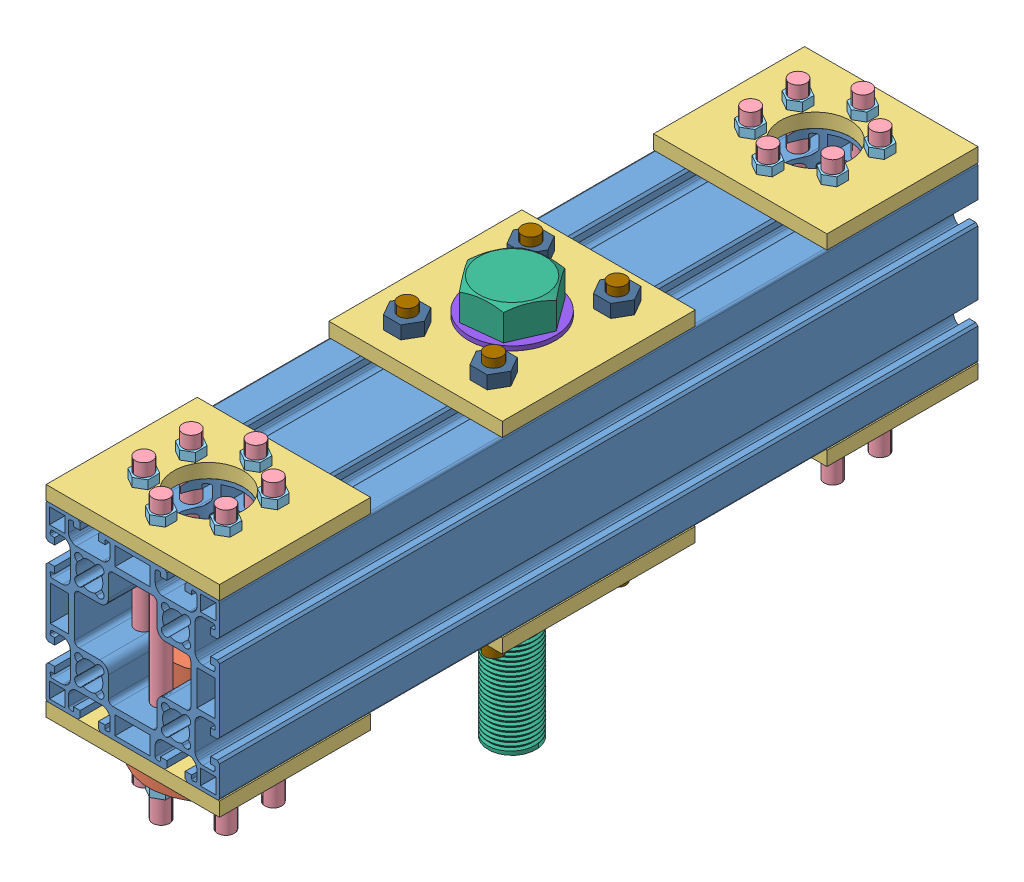
SolidWorks assembly loading_beaM_assembly, configuration Default. Lengths in mm.
Overall size (80.06 184 350).
17 component instances, 10 part files, 45 mates.
Components (placement in the parent):
- AL_profile350-1: AL_profile350 [Default] at (-39.8812 -129.6235 350) x (1 0 0) z (0 1 0) size (80 350 80)
- bearing for thread-1: bearing for thread [Default] at (-39.9881 -184.4189 315) size (55 44.2 55)
- metal piece-1: metal piece [Default] at (-39.9406 -79.4189 175) x (1 0 0) z (0 -1 0) size (80 350 6.5)
- side_threa_rods-1: side_threa_rods [Default] at (-39.9881 -199.4938 315) size (45.68 130 51.54)
- side_threa_rods-2: side_threa_rods [Default] at (-39.9881 -199.4938 35) x (0.5 0 -0.866025) z (0.866025 0 0.5) size (45.68 130 51.54)
- metal piece-3: metal piece [Default] at (-39.9406 -165.9189 175) x (1 0 0) z (0 -1 0) size (80 350 6.5)
- bearing for thread-2: bearing for thread [Default] at (-39.9881 -184.4189 35) size (55 44.2 55)
- nuts_7.8-1: nuts_7.8 [Default] at (-39.9881 -188.4189 315) size (47.17 4 54.47)
- nuts_7.8-2: nuts_7.8 [Default] at (-39.9881 -188.4189 35) size (47.17 4 54.47)
- nuts_7.8-3: nuts_7.8 [Default] at (-39.9881 -79.4189 35) size (47.17 4 54.47)
- nuts_7.8-4: nuts_7.8 [Default] at (-39.9881 -79.4189 315) x (0.5 0 0.866025) z (-0.866025 0 0.5) size (47.17 4 54.47)
- central_boltwithnut-1: central_boltwithnut [Default] at (-39.9406 -77.4189 175) x (-0.993893 0 0.11035) z (0.11035 0 0.993893) size (36.95 184 32)
- central_nutforbolt-1: central_nutforbolt [Default] at (-39.9406 -175.2412 175) x (0.894237 0 -0.447594) z (0.447594 0 0.894237) size (41.05 18.73 38)
- centralwaher-1: centralwaher [Default] at (-39.9406 -79.4189 175) size (40 2 40)
- central4bolts-1: central4bolts [Default] at (-39.3156 -189.4938 174.9932) size (47.9 120 65.04)
- M8nut-4: M8nut [Default] at (-59.8908 -79.4189 146.4879) size (55.9 6 70.85)
- M8nut-5: M8nut [Default] at (-59.8908 -178.4189 146.4879) size (55.9 6 70.85)
Mates (geometry in assembly coordinates):
- Coincident1: coincident anti-aligned: plane of AL_profile350-1 through (-39.8812 -129.6235 0) normal (0 0 -1)
- Coincident2: coincident aligned: plane of AL_profile350-1 through (0 -129.6235 0) normal (1 0 0)
- Concentric1: concentric anti-aligned: cylinder of AL_profile350-1 through (-39.9881 -165.9189 315) axis (0 1 0) radius 16; circle of metal piece-3
- Concentric2: concentric anti-aligned: circle of metal piece-1; circle of AL_profile350-1
- Concentric3: concentric anti-aligned: circle of AL_profile350-1; circle of metal piece-1
- Concentric4: concentric anti-aligned: circle of AL_profile350-1; circle of metal piece-3
- Concentric5: concentric anti-aligned: circle of bearing for thread-1; circle of metal piece-3
- Concentric6: concentric anti-aligned: circle of bearing for thread-1; circle of metal piece-3
- Concentric7: concentric anti-aligned: circle of metal piece-1; circle of side_threa_rods-1
- Concentric8: concentric aligned: circle of metal piece-1; cylinder of side_threa_rods-1 through (-58.9281 -69.4938 325.935) axis (0 -1 0) radius 3.9
- Concentric9: concentric anti-aligned: circle of metal piece-1; circle of side_threa_rods-2
- Concentric10: concentric anti-aligned: cylinder of metal piece-1 through (-39.9881 -79.4189 56.87) axis (0 -1 0) radius 3.9; circle of side_threa_rods-2
- Concentric13: concentric anti-aligned: circle of metal piece-3; circle of bearing for thread-2
- Concentric14: concentric aligned: circle of side_threa_rods-2; circle of bearing for thread-2
- Concentric20: concentric aligned: circle of side_threa_rods-1; circle of nuts_7.8-1
- Concentric21: concentric aligned: circle of side_threa_rods-1; circle of nuts_7.8-1
- Coincident7: coincident anti-aligned: plane of bearing for thread-1 through (-39.9881 -172.4189 315) normal (0 1 0); plane of metal piece-3 through (-39.9406 -172.4189 175) normal (0 -1 0)
- Coincident8: coincident anti-aligned: plane of bearing for thread-1 through (-39.9881 -184.4189 315) normal (0 -1 0); plane of nuts_7.8-1 through (-39.9881 -184.4189 315) normal (0 1 0)
- Concentric22: concentric aligned: circle of side_threa_rods-2; circle of nuts_7.8-2
- Concentric23: concentric aligned: circle of side_threa_rods-2; circle of nuts_7.8-2
- Coincident11: coincident aligned: circle of bearing for thread-1; plane of bearing for thread-2 through (-39.9881 -172.4189 35) normal (0 1 0)
- Coincident12: coincident: line of nuts_7.8-1 through (-16.4022 -184.4189 301.3827) axis (-0.866025 0 -0.5); plane of nuts_7.8-2 through (-39.9881 -184.4189 35) normal (0 1 0)
- Coincident13: coincident anti-aligned: plane of side_threa_rods-1 through (-21.0482 -199.4938 325.935) normal (0 -1 0); circle of side_threa_rods-2
- Concentric24: concentric aligned: circle of side_threa_rods-1; circle of nuts_7.8-4
- Concentric25: concentric aligned: circle of side_threa_rods-1; circle of nuts_7.8-4
- Coincident16: coincident anti-aligned: plane of metal piece-1 through (-39.9406 -79.4189 175) normal (0 1 0); plane of nuts_7.8-4 through (-39.9881 -79.4189 315) normal (0 -1 0)
- Concentric26: concentric aligned: circle of side_threa_rods-2; circle of nuts_7.8-3
- Concentric27: concentric aligned: circle of side_threa_rods-2; circle of nuts_7.8-3
- Coincident20: coincident: plane of nuts_7.8-3 through (-39.9881 -79.4189 35) normal (0 -1 0); line of nuts_7.8-4 through (-16.4022 -79.4189 323.2527) axis (-0.866025 0 -0.5)
- Screw2: screw = 2 aligned: cylinder of central_boltwithnut-1 through (-39.9406 -247.4189 175) axis (0 1 0) radius 11; cylinder of central_nutforbolt-1 through (-39.9406 -191.2412 175) axis (0 1 0) radius 11
- Concentric29: concentric anti-aligned: circle of metal piece-3; circle of central_nutforbolt-1
- Concentric30: concentric anti-aligned: circle of metal piece-1; circle of centralwaher-1
- Coincident24: coincident anti-aligned: plane of central_boltwithnut-1 through (-39.9406 -77.4189 175) normal (0 -1 0); plane of centralwaher-1 through (-39.9406 -77.4189 175) normal (0 1 0)
- Coincident27: coincident anti-aligned: plane of metal piece-1 through (-39.9406 -79.4189 175) normal (0 1 0); plane of centralwaher-1 through (-39.9406 -79.4189 175) normal (0 -1 0)
- Coincident28: coincident anti-aligned: plane of AL_profile350-1 through (-39.8812 -165.9189 0) normal (0 -1 0); plane of metal piece-3 through (-39.9406 -165.9189 175) normal (0 1 0)
- Lock1: lock: unknown of side_threa_rods-2; unknown of nuts_7.8-2
- Concentric31: concentric anti-aligned: circle of metal piece-1; circle of central4bolts-1
- Concentric32: concentric anti-aligned: circle of metal piece-1; circle of central4bolts-1
- Coincident33: coincident aligned: plane of side_threa_rods-2 through (-58.9281 -69.4938 45.935) normal (0 1 0); plane of central4bolts-1 through (-59.8908 -69.4938 146.4879) normal (0 1 0)
- Concentric33: concentric aligned: circle of central4bolts-1; circle of M8nut-4
- Concentric34: concentric aligned: circle of central4bolts-1; circle of M8nut-4
- Concentric35: concentric aligned: circle of central4bolts-1; circle of M8nut-5
- Concentric36: concentric aligned: circle of M8nut-4; circle of M8nut-5
- Coincident38: coincident anti-aligned: plane of metal piece-3 through (-39.9406 -172.4189 175) normal (0 -1 0); plane of M8nut-5 through (-59.8908 -172.4189 146.4879) normal (0 1 0)
- Coincident39: coincident anti-aligned: plane of metal piece-1 through (-39.9406 -79.4189 175) normal (0 1 0); plane of M8nut-4 through (-59.8908 -79.4189 146.4879) normal (0 -1 0)
